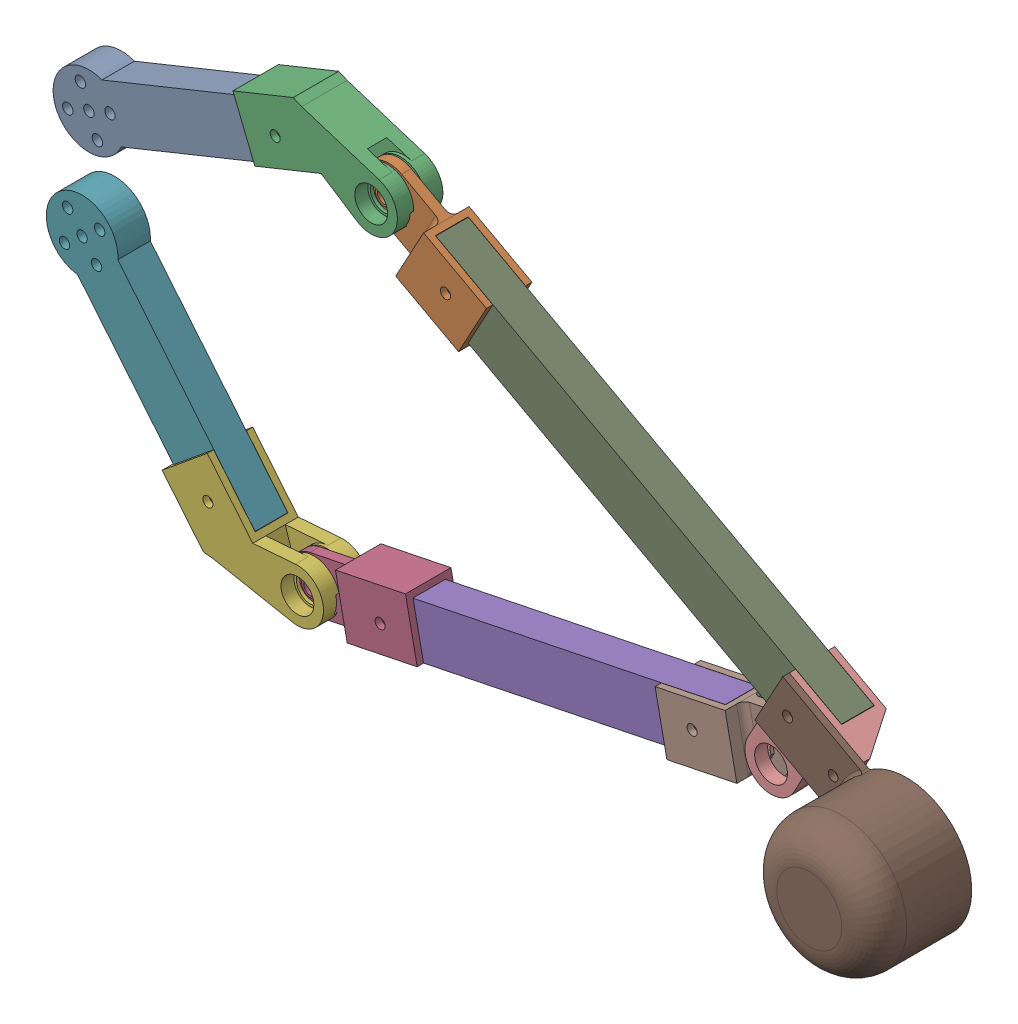
SolidWorks assembly leg_assembly, configuration Default. Lengths in mm.
Overall size (298.35 162.64 44).
11 component instances, 7 part files, 27 mates.
Components (placement in the parent):
- thigh-1: thigh [Default] at (38.0166 -5.5931 15.1402) x (0.927184 0.374607 0) z (0 0 -1) size (85 22 10)
- thigh_clamp-3: thigh_clamp [Default] at (146.6171 11.3856 10.1402) x (-0.879071 0.476691 0) z (0.476691 0.879071 0) size (44.05 14 18.26)
- shank_clamp-1: shank_clamp [Default] at (115.9001 25.8739 10.1402) x (0.927184 0.374607 0) z (0.374607 -0.927184 0) size (44.19 14 32.19)
- thigh_clamp-4: thigh_clamp [Default] at (125.3117 -94.8082 10.1402) x (-0.979647 -0.200726 0) z (0.200726 -0.979647 0) size (44.05 14 18.26)
- shank-2: shank [Default] at (185.0702 -82.5639 5.1402) x (0.979647 0.200726 0) z (0 0 1) size (118 16 10)
- shank_clamp-3: shank_clamp [Default] at (91.6889 -95.6994 10.1402) x (0.636 -0.771689 0) z (0.771689 0.636 0) size (44.19 14 32.19)
- thigh-4: thigh [Default] at (38.2649 -30.8775 5.1402) x (0.636 -0.771689 0) z (0 0 1) size (85 22 10)
- thigh_clamp-5: thigh_clamp [Default] at (244.8287 -70.3197 10.1402) x (0.979647 0.200726 0) z (-0.200726 0.979647 0) size (44.05 14 18.26)
- shank_long-1: shank_long [Default] at (210.7893 -23.4128 15.1402) x (0.879071 -0.476691 0) z (0 0 -1) size (142 16 10)
- shank_clamp_bottom-1: shank_clamp_bottom [Default] at (261.4039 -62.2351 10.1402) x (-0.476691 -0.879071 0) z (-0.879071 0.476691 0) size (34.55 14 26.05)
- ish50g-1: ish50g [Default] at (299.0988 -72.4377 17.1402) x (-0.476691 -0.879071 0) z (-0.879071 0.476691 0) size (40 30 66)
Mates (geometry in assembly coordinates):
- Distance15: distance = 0.1 mm anti-aligned: plane of thigh-1 through (117.0425 17.7072 5.1402) normal (0.927184 0.374607 0); plane of shank_clamp-1 through (114.1384 25.1621 10.1402) normal (-0.927184 -0.374607 0)
- Concentric1: concentric aligned: circle of shank_clamp-1; circle of thigh_clamp-3
- Concentric2: concentric aligned: circle of thigh_clamp-4; circle of shank_clamp-3
- Distance2: distance = 1.5 mm anti-aligned: plane of thigh_clamp-4 through (111.5966 -97.6183 8.6402) normal (0 0 -1); plane of shank_clamp-3 through (111.5966 -97.6183 7.1402) normal (0 0 1)
- Distance18: distance = 0.1 mm anti-aligned: plane of shank_clamp-3 through (90.4805 -94.2332 10.1402) normal (-0.636 0.771689 0); plane of thigh-4 through (96.5904 -89.068 15.1402) normal (0.636 -0.771689 0)
- Distance21: distance = 0.1 mm anti-aligned: plane of thigh_clamp-4 through (127.173 -94.4268 10.1402) normal (0.979647 0.200726 0); plane of shank-2 through (125.6652 -86.5695 15.1402) normal (-0.979647 -0.200726 0)
- Distance25: distance = 0.1 mm anti-aligned: plane of shank-2 through (241.2636 -62.8839 15.1402) normal (0.979647 0.200726 0); plane of thigh_clamp-5 through (242.9674 -70.701 10.1402) normal (-0.979647 -0.200726 0)
- Distance28: distance = 0.1 mm anti-aligned: plane of shank_long-1 through (144.5618 3.3996 5.1402) normal (-0.879071 0.476691 0); plane of thigh_clamp-3 through (148.2874 10.4799 10.1402) normal (0.879071 -0.476691 0)
- Distance9: distance = 0.1 mm anti-aligned: plane of shank_long-1 through (144.5618 3.3996 5.1402) normal (-0.476691 -0.879071 0); plane of shank_clamp_bottom-1 through (262.3096 -60.5648 10.1402) normal (0.476691 0.879071 0)
- Distance10: distance = 0.05 mm anti-aligned: plane of shank_long-1 through (210.7893 -23.4128 5.1402) normal (0 0 -1); plane of shank_clamp_bottom-1 through (269.3422 -64.3784 5.0902) normal (0 0 1)
- Concentric4: concentric anti-aligned: circle of thigh_clamp-5; circle of shank_clamp_bottom-1
- Distance5: distance = 1.5 mm anti-aligned: plane of thigh_clamp-5 through (258.5438 -67.5095 11.6402) normal (0 0 1); plane of shank_clamp_bottom-1 through (258.5438 -67.5095 13.1402) normal (0 0 -1)
- Distance6: distance = 0.5 mm anti-aligned: plane of shank_clamp-1 through (134.3102 18.0593 8.1402) normal (0 0 1); plane of thigh_clamp-3 through (134.3102 18.0593 8.6402) normal (0 0 -1)
- Distance8: distance = 0.1 mm anti-aligned: plane of shank_long-1 through (269.3898 -64.2904 5.1402) normal (0.879071 -0.476691 0); plane of shank_clamp_bottom-1 through (268.5244 -66.0963 10.1402) normal (-0.879071 0.476691 0)
- Distance19: distance = 0.1 mm anti-aligned: plane of shank_clamp-3 through (85.4382 -100.851 10.1402) normal (0.771689 0.636 0); plane of thigh-4 through (84.2434 -99.244 15.1402) normal (-0.771689 -0.636 0)
- Distance20: distance = 0.05 mm anti-aligned: plane of thigh-4 through (43.3529 -37.051 15.1402) normal (0 0 1); plane of shank_clamp-3 through (84.307 -99.3212 15.1902) normal (0 0 -1)
- Distance22: distance = 0.1 mm anti-aligned: plane of thigh_clamp-4 through (123.6858 -86.873 10.1402) normal (0.200726 -0.979647 0); plane of shank-2 through (125.6652 -86.5695 15.1402) normal (-0.200726 0.979647 0)
- Distance23: distance = 0.05 mm anti-aligned: plane of shank-2 through (185.0702 -82.5639 5.1402) normal (0 0 -1); plane of thigh_clamp-4 through (125.5672 -86.5896 5.0902) normal (0 0 1)
- Distance26: distance = 0.05 mm anti-aligned: plane of shank-2 through (185.0702 -82.5639 15.1402) normal (0 0 1); plane of thigh_clamp-5 through (244.5732 -78.5382 15.1902) normal (0 0 -1)
- Distance27: distance = 0.1 mm anti-aligned: plane of thigh_clamp-5 through (246.4546 -78.2548 10.1402) normal (-0.200726 0.979647 0); plane of shank-2 through (128.8768 -102.2439 15.1402) normal (0.200726 -0.979647 0)
- Distance29: distance = 0.1 mm anti-aligned: plane of shank_long-1 through (144.5618 3.3996 5.1402) normal (-0.476691 -0.879071 0); plane of thigh_clamp-3 through (142.756 4.2651 10.1402) normal (0.476691 0.879071 0)
- Distance30: distance = 0.05 mm anti-aligned: plane of thigh_clamp-3 through (144.4739 3.4473 5.0902) normal (0 0 1); plane of shank_long-1 through (210.7893 -23.4128 5.1402) normal (0 0 -1)
- Distance31: distance = 0.1 mm anti-aligned: plane of thigh-1 through (111.0488 32.5422 5.1402) normal (-0.374607 0.927184 0); plane of shank_clamp-1 through (112.8657 33.3841 10.1402) normal (0.374607 -0.927184 0)
- Distance32: distance = 0.05 mm anti-aligned: plane of shank_clamp-1 through (111.1416 32.5796 5.0902) normal (0 0 1); plane of thigh-1 through (45.4341 -2.5962 5.1402) normal (0 0 -1)
- Coincident1: coincident anti-aligned: plane of shank_clamp_bottom-1 through (261.4039 -62.2351 17.1402) normal (0 0 1); plane of ish50g-1 through (299.0988 -72.4377 17.1402) normal (0 0 -1)
- Coincident2: coincident anti-aligned: line of shank_clamp_bottom-1 through (262.9518 -42.5983 17.1402) axis (-0.476691 -0.879071 0); line of ish50g-1 through (254.3713 -58.4215 17.1402) axis (0.476691 0.879071 0)
- Coincident3: coincident anti-aligned: line of shank_clamp_bottom-1 through (285.8076 -54.9922 17.1402) axis (-0.879071 0.476691 0); line of ish50g-1 through (262.9518 -42.5983 17.1402) axis (0.879071 -0.476691 0)
